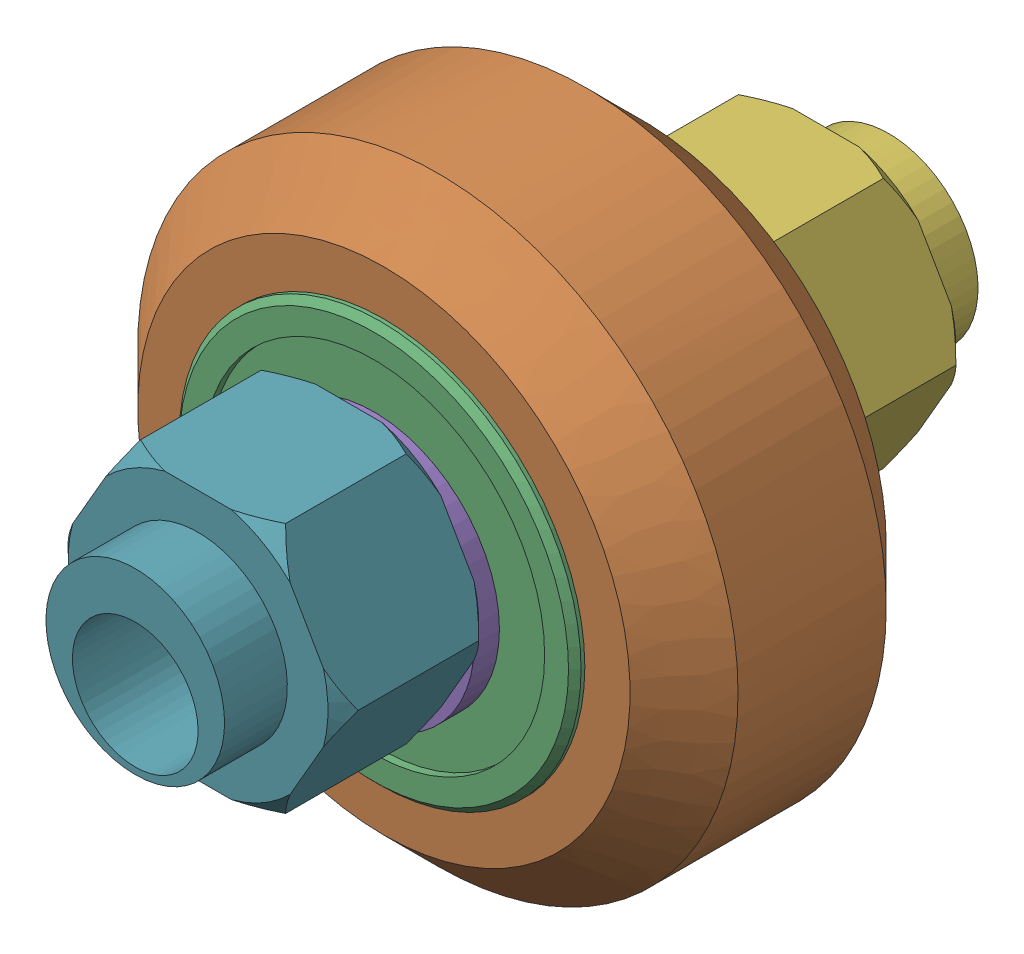
SolidWorks assembly Outboard Wheel Stack_2, configuration Default. Lengths in mm.
Overall size (23.9 23.9 30).
9 component instances, 4 part files, 0 mates.
Components (placement in the parent):
- Xtreme Solid V Wheel Kit Assembly_6-1: Xtreme Solid V Wheel Kit Assembly_6 [Default] at origin size (23.9 23.9 13)
  - Precision Shim - 10x5x1mm-1: Precision Shim - 10x5x1mm [Default] at origin size (10 10 1)
  - Xtreme Solid V Wheel Assembly_6-1: Xtreme Solid V Wheel Assembly_6 [Default] at (115.15 55.79 -23.5) size (23.9 23.9 11)
    - Xtreme Solid V Wheel-1: Xtreme Solid V Wheel [Default] at (-115.15 -55.79 30) x (0 0 1) z (-1 0 0) size (10.2 23.9 23.9)
    - Wheel+Kit+-+5x16x5mm+Sealed+Radial+Ball+Bearing.step.f3d-1: Wheel+Kit+-+5x16x5mm+Sealed+Radial+Ball+Bearing.step.f3d [Default] at (-115.15 -55.79 30) x (0 1 0) z (-1 0 0) size (16 5 16)
    - Wheel+Kit+-+5x16x5mm+Sealed+Radial+Ball+Bearing.step.f3d-2: Wheel+Kit+-+5x16x5mm+Sealed+Radial+Ball+Bearing.step.f3d [Default] at (-115.15 -55.79 30) x (0 1 0) z (1 0 0) size (16 5 16)
  - Precision Shim - 10x5x1mm-2: Precision Shim - 10x5x1mm [Default] at (0 0 12) size (10 10 1)
- Eccentric Spacer 6mm-1: Eccentric Spacer 6mm [Default] at (0 0.79 -6) x (1 0 0) z (0 -1 0) size (11.55 8.5 10)
- Eccentric Spacer 6mm-2: Eccentric Spacer 6mm [Default] at (0 0.79 19) x (-1 0 0) z (0 -1 0) size (11.55 8.5 10)
